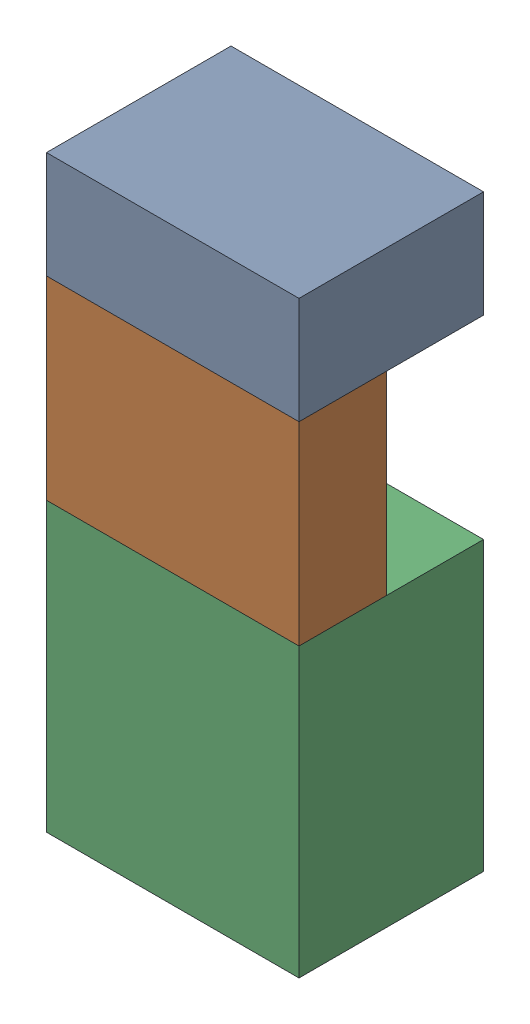
SolidWorks assembly SUP_K6, configuration Default. Lengths in mm.
Overall size (13 30.3 9.5).
6 component instances, 3 part files, 0 mates.
Components (placement in the parent):
- 1151724928-1: 1151724928 [Default] at (83.185 41.975 0) size (13 5.5 9.5)
  - Extruded_2-1: Extruded_2 [Default] at origin size (13 5.5 9.5)
- 1151725064-1: 1151725064 [Default] at (83.185 34.225 5) size (13 10 4.5)
  - Extruded_3-1: Extruded_3 [Default] at origin size (13 10 4.5)
- 1151724792-1: 1151724792 [Default] at (83.185 21.825 0) size (13 14.8 9.5)
  - Extruded_4-1: Extruded_4 [Default] at origin size (13 14.8 9.5)
